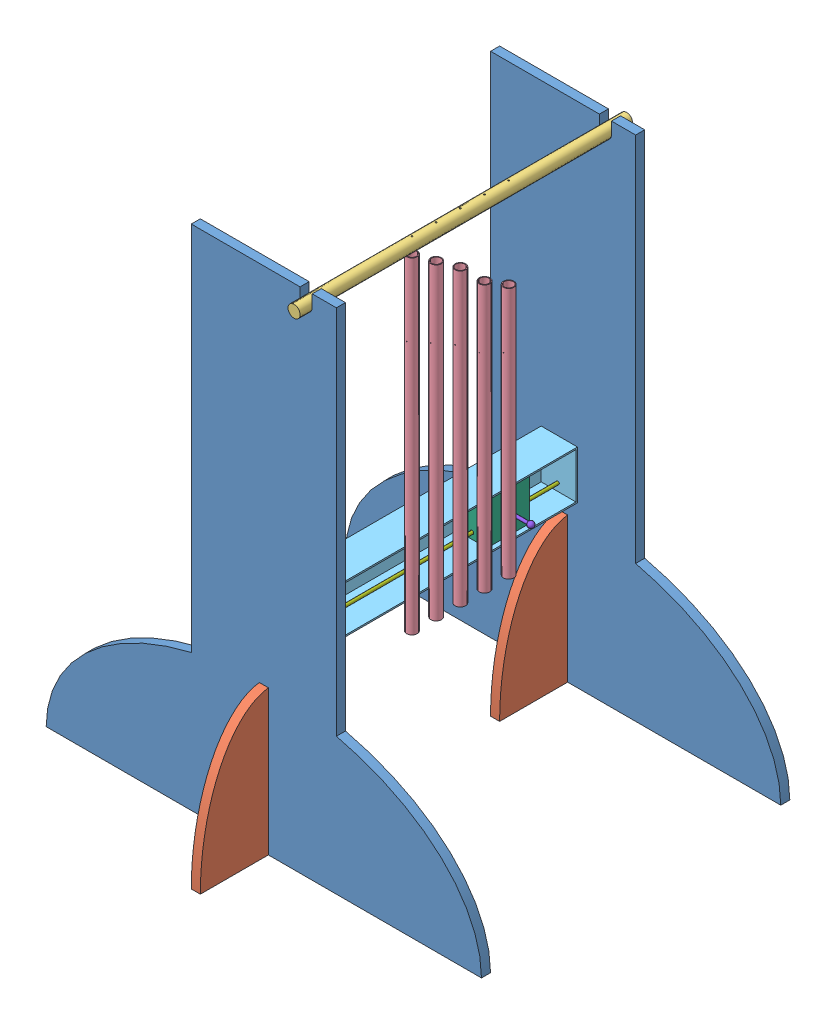
SolidWorks assembly w9-assembly, configuration Default. Lengths in mm.
Overall size (914.4 1066.8 933.45).
16 component instances, 8 part files, 32 mates.
Components (placement in the parent):
- SideSupport-1: SideSupport [Default] at origin size (914.4 1066.8 19.05)
- CrossBrace-1: CrossBrace [Default] x (0 0 1) z (-1 0 0) size (304.8 304.2 19.05)
- dowell-1: dowell [Default] at (88.9 1041.4 34.925) size (25.4 25.4 698.5)
- SideSupport-2: SideSupport [Default] at (0 0 -628.65) size (914.4 1066.8 19.05)
- CrossBrace-2: CrossBrace [Default] at (0 0 -628.65) x (0 0 1) z (-1 0 0) size (304.8 304.2 19.05)
- Pipe1-1: Pipe1 [27] at (88.9 1022.35 -212.725) size (22.23 685.8 22.23)
- Pipe1-2: Pipe1 [25] at (88.9 984.25 -263.525) size (22.23 647.7 22.23)
- Pipe1-3: Pipe1 [24] at (88.9 947.7375 -314.325) size (22.23 611.19 22.23)
- Pipe1-4: Pipe1 [22] at (88.9 896.9375 -365.125) size (22.23 560.39 22.23)
- Pipe1-5: Pipe1 [20] at (88.9 865.1875 -415.925) size (22.23 528.64 22.23)
- w9-BoxAssembly-1: w9-BoxAssembly [Default] at (-7.9375 387.35 -314.325) size (76.2 101.6 609.6) (flexible)
  - BoxFrame-1: BoxFrame [Default] at origin size (76.2 101.6 609.6)
  - BoxStage-1: BoxStage [Default] at (-31.75 0 -165.6288) size (63.5 88.9 88.9)
  - BoxRod-1: BoxRod [Default] at (0 31.75 -304.8) size (6.35 6.35 609.6)
  - BoxRod-2: BoxRod [Default] at (0 -31.75 -304.8) size (6.35 6.35 609.6)
- Clapper-1: Clapper [Default] at (71.4375 387.35 -479.9538) x (1 0 0) z (0 0.610345 -0.792136) size (120.65 12.7 12.7)
Mates (geometry in assembly coordinates):
- Width1: width anti-aligned: plane of CrossBrace-1 through (9.525 304.8 9.525) normal (0 0 -1); plane of CrossBrace-1 through (9.525 304.8 -9.525) normal (0 0 1); plane of SideSupport-1 through (0 0 9.525) normal (0 0 1); plane of SideSupport-1 through (0 0 -9.525) normal (0 0 -1)
- Coincident1: coincident aligned: plane of SideSupport-1 through (-457.2 0 9.525) normal (0 -1 0); plane of CrossBrace-1 through (-9.525 0 -152.4) normal (0 -1 0)
- Coincident2: coincident anti-aligned: plane of SideSupport-1 through (9.525 0 -9.525) normal (-1 0 0); plane of CrossBrace-1 through (9.525 0 0) normal (1 0 0)
- Concentric1: concentric aligned: cylinder of SideSupport-1 through (88.9 1041.4 -9.525) axis (0 0 1) radius 12.7; cylinder of dowell-1 through (88.9 1041.4 -663.575) axis (0 0 1) radius 12.7
- Distance1: distance = 25.4 mm aligned: plane of SideSupport-1 through (0 0 9.525) normal (0 0 1); plane of dowell-1 through (88.9 1041.4 34.925) normal (0 0 1)
- Concentric2: concentric aligned: cylinder of dowell-1 through (88.9 1041.4 -663.575) axis (0 0 1) radius 12.7; cylinder of SideSupport-2 through (88.9 1041.4 -638.175) axis (0 0 1) radius 12.7
- Distance2: distance = 25.4 mm aligned: plane of dowell-1 through (88.9 1041.4 -663.575) normal (0 0 -1); plane of SideSupport-2 through (0 0 -638.175) normal (0 0 -1)
- Coincident5: coincident aligned: plane of SideSupport-1 through (152.4 1066.8 9.525) normal (1 0 0); plane of SideSupport-2 through (152.4 1066.8 -619.125) normal (1 0 0)
- Width2: width aligned: plane of SideSupport-2 through (0 0 -619.125) normal (0 0 1); plane of SideSupport-2 through (0 0 -638.175) normal (0 0 -1); plane of CrossBrace-2 through (9.525 304.8 -638.175) normal (0 0 1); plane of CrossBrace-2 through (9.525 304.8 -619.125) normal (0 0 -1)
- Coincident6: coincident aligned: plane of SideSupport-2 through (-457.2 0 -619.125) normal (0 -1 0); plane of CrossBrace-2 through (-9.525 0 -781.05) normal (0 -1 0)
- Coincident7: coincident anti-aligned: plane of SideSupport-2 through (9.525 0 -638.175) normal (-1 0 0); plane of CrossBrace-2 through (9.525 0 -628.65) normal (1 0 0)
- Parallel1: parallel aligned: plane of SideSupport-1 through (152.4 1066.8 9.525) normal (1 0 0); plane of dowell-1 through (88.9 1041.4 34.925) normal (1 0 0)
- Coincident9: coincident aligned: plane of dowell-1 through (88.9 1041.4 34.925) normal (1 0 0); plane of Pipe1-1 through (88.9 1022.35 -212.725) normal (1 0 0)
- Coincident10: coincident aligned: plane of Pipe1-1 through (88.9 1022.35 -212.725) normal (1 0 0); plane of Pipe1-2 through (88.9 984.25 -263.525) normal (1 0 0)
- Coincident12: coincident aligned: plane of Pipe1-1 through (88.9 1022.35 -212.725) normal (1 0 0); plane of Pipe1-3 through (88.9 947.7375 -314.325) normal (1 0 0)
- Coincident13: coincident aligned: plane of Pipe1-1 through (88.9 1022.35 -212.725) normal (1 0 0); plane of Pipe1-4 through (88.9 896.9375 -365.125) normal (1 0 0)
- Coincident14: coincident aligned: plane of Pipe1-1 through (88.9 1022.35 -212.725) normal (1 0 0); plane of Pipe1-5 through (88.9 865.1875 -415.925) normal (1 0 0)
- Coincident15: coincident aligned: plane of Pipe1-1 through (88.9 336.55 -212.725) normal (0 -1 0); plane of Pipe1-2 through (88.9 336.55 -263.525) normal (0 -1 0)
- Coincident16: coincident aligned: plane of Pipe1-1 through (88.9 336.55 -212.725) normal (0 -1 0); plane of Pipe1-3 through (88.9 336.55 -314.325) normal (0 -1 0)
- Coincident17: coincident aligned: plane of Pipe1-1 through (88.9 336.55 -212.725) normal (0 -1 0); plane of Pipe1-4 through (88.9 336.55 -365.125) normal (0 -1 0)
- Coincident18: coincident aligned: plane of Pipe1-1 through (88.9 336.55 -212.725) normal (0 -1 0); plane of Pipe1-5 through (88.9 336.55 -415.925) normal (0 -1 0)
- Distance3: distance = 50.8 mm aligned: plane of Pipe1-2 through (88.9 984.25 -263.525) normal (0 0 1); plane of Pipe1-1 through (88.9 1022.35 -212.725) normal (0 0 1)
- Distance4: distance = 101.6 mm aligned: plane of Pipe1-1 through (88.9 1022.35 -212.725) normal (0 0 1); plane of Pipe1-3 through (88.9 947.7375 -314.325) normal (0 0 1)
- Distance5: distance = 152.4 mm aligned: plane of Pipe1-4 through (88.9 896.9375 -365.125) normal (0 0 1); plane of Pipe1-1 through (88.9 1022.35 -212.725) normal (0 0 1)
- Distance6: distance = 203.2 mm aligned: plane of Pipe1-5 through (88.9 865.1875 -415.925) normal (0 0 1); plane of Pipe1-1 through (88.9 1022.35 -212.725) normal (0 0 1)
- Distance7: distance = 19.05 mm aligned: plane of dowell-1 through (88.9 1041.4 34.925) normal (0 1 0); plane of Pipe1-1 through (88.9 1022.35 -212.725) normal (0 1 0)
- Concentric3: concentric aligned: cylinder of dowell-1 through (88.9 1028.7 -212.725) axis (0 1 0) radius 1.5875; cylinder of Pipe1-1 through (88.9 336.55 -212.725) axis (0 1 0) radius 11.1125
- Coincident24: coincident anti-aligned: plane of SideSupport-1 through (0 0 -9.525) normal (0 0 -1); plane of w9-BoxAssembly-1/BoxFrame-1 through (30.1625 438.15 -9.525) normal (0 0 1)
- Coincident26: coincident aligned: plane of Pipe1-1 through (88.9 336.55 -212.725) normal (0 -1 0); plane of w9-BoxAssembly-1/BoxFrame-1 through (30.1625 336.55 -619.125) normal (0 -1 0)
- Concentric4: concentric aligned: cylinder of w9-BoxAssembly-1/BoxStage-1 through (-39.6875 387.35 -479.9538) axis (1 0 0) radius 3.175; cylinder of Clapper-1 through (-42.8625 387.35 -479.9538) axis (1 0 0) radius 3.175
- Coincident29: coincident anti-aligned: plane of w9-BoxAssembly-1/BoxFrame-1 through (-42.8625 387.35 -314.325) normal (1 0 0); plane of Clapper-1 through (-42.8625 387.35 -479.9538) normal (-1 0 0)
- Distance8: distance = 11.1125 mm aligned: plane of Pipe1-1 through (88.9 1022.35 -212.725) normal (1 0 0); sphere of Clapper-1
